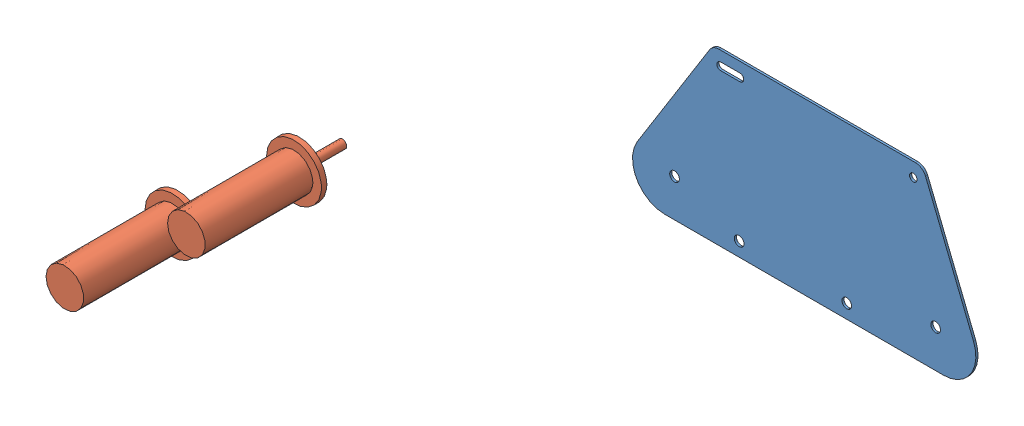
SolidWorks assembly Assem1, configuration Default. Lengths in mm.
Overall size (436.92 172.41 436.84).
3 component instances, 2 part files, 0 mates.
Components (placement in the parent):
- Plate-2: Plate [Default] at (-48.8766 -122.4142 -286.9971) size (318.97 158 2)
- DriveMotor-2: DriveMotor [Default] at (-83.9819 -5.2654 -34.8071) size (51 51 145)
- DriveMotor-3: DriveMotor [Default] at (-117.2076 -25.0481 44.8418) size (51 51 145)
